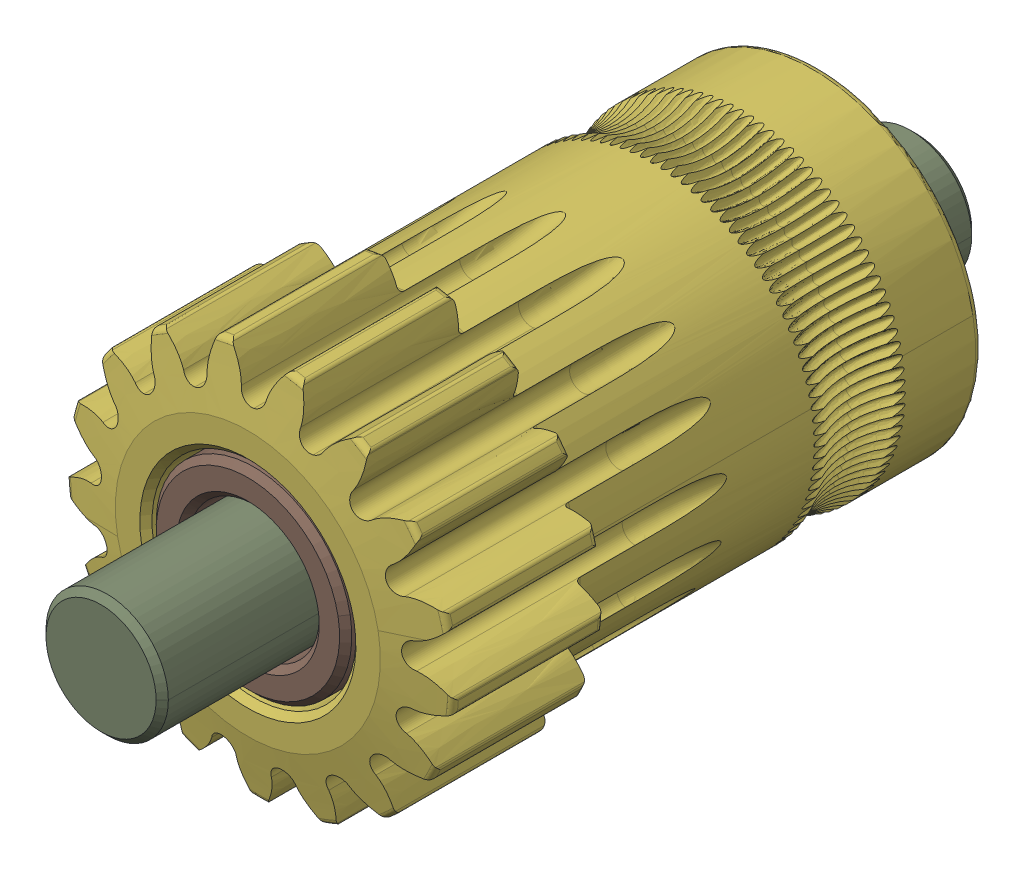
SolidWorks assembly idler_gear_assy_sherpa_mini_a3_r9c, configuration 默认. Lengths in mm.
Overall size (11.06 11.02 20).
4 component instances, 3 part files, 0 mates.
Components (placement in the parent):
- needle_bearing_idler_gear_assy_sherpa_mini_a3_r9c-1: needle_bearing_idler_gear_assy_sherpa_mini_a3_r9c [默认] at (0 0 -4.35) x (0.982973 0.18375 0) z (0 0 1) size (4.9 4.91 6.5)
- shaft_idler_gear_assy_sherpa_mini_a3_r9c-1: shaft_idler_gear_assy_sherpa_mini_a3_r9c [默认] at origin size (3 3 20)
- needle_bearing_idler_gear_assy_sherpa_mini_a3_r9c-2: needle_bearing_idler_gear_assy_sherpa_mini_a3_r9c [默认] at (0 0 3.15) x (0.982973 0.18375 0) z (0 0 1) size (4.9 4.91 6.5)
- idler_gear_idler_gear_assy_sherpa_mini_a3_r9c-1: idler_gear_idler_gear_assy_sherpa_mini_a3_r9c [默认] at (0 0 2.4) x (0.982973 0.18375 0) z (0 0 1) size (9.48 9.44 14)
